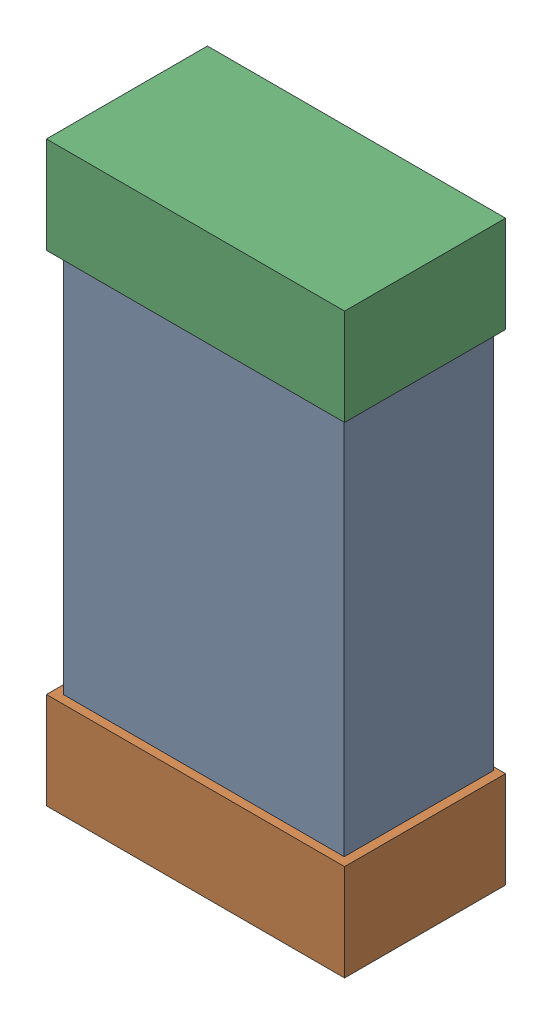
SolidWorks assembly C31, configuration Default. Lengths in mm.
Overall size (0.85 1.65 0.46).
6 component instances, 2 part files, 0 mates.
Components (placement in the parent):
- 432124816_40-1: 432124816_40 [Default] at (12.7251 19.4533 -0.8615) size (0.8 1.5 0.42)
  - Extruded (1)-1: Extruded (1) [Default] at origin size (0.8 1.5 0.42)
- 432138512_80-1: 432138512_80 [Default] at (12.7251 18.7675 -0.8715) size (0.85 0.28 0.46)
  - Extruded-1: Extruded [Default] at origin size (0.85 0.28 0.46)
- 432138512_81-1: 432138512_81 [Default] at (12.7251 20.1391 -0.8715) size (0.85 0.28 0.46)
  - Extruded-1: Extruded [Default] at origin size (0.85 0.28 0.46)
